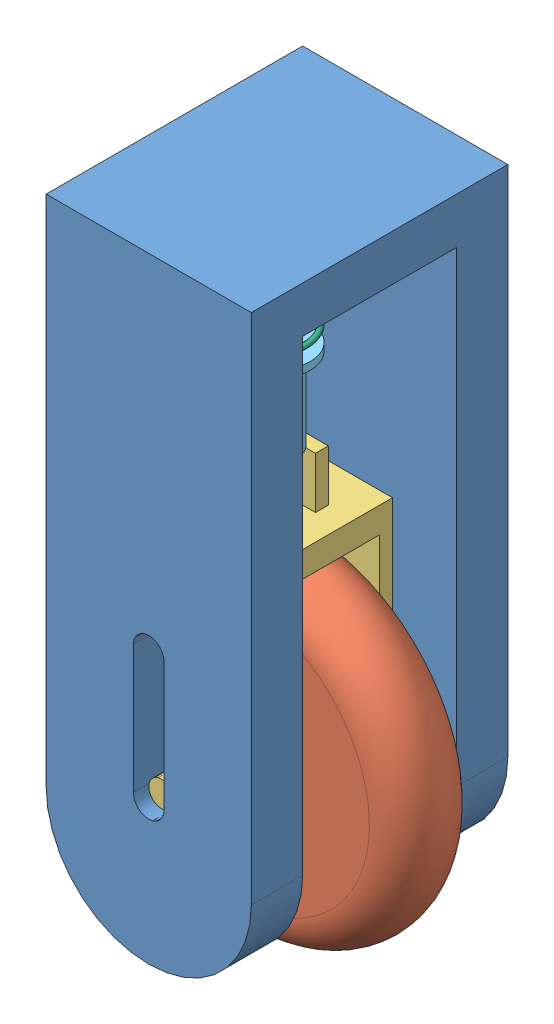
SolidWorks assembly Assem2, configuration Default. Lengths in mm.
Overall size (135.04 252.52 100).
6 component instances, 6 part files, 14 mates.
Components (placement in the parent):
- wheel-1: wheel [Default] at origin size (80 240 100)
- Part1^Assem2-1: Part1^Assem2 [Default] at (0 -125 0) x (0.999729 -0.023276 0) z (0 0 1) size (132 132 30) (virtual)
- Part2^Assem2-1: Part2^Assem2 [Default] at (0 -130 0) size (40 100 90) (virtual)
- Part3^Assem2-1: Part3^Assem2 [Default] at (0 -13 0) size (26 55 26) (virtual)
- Part4^Assem2-1: Part4^Assem2 [Default] at (0 -30 0) size (26 53 26) (virtual)
- Part7^Assem2-1: Part7^Assem2 [Default] at (0 5 0) x (1 0 0) z (0 1 0) size (30.02 26.11 26) (virtual)
Mates (geometry in assembly coordinates):
- Slot1: slot: cylinder of Part2^Assem2-1 through (0 -125 45) axis (0 0 -1) radius 5; plane of wheel-1 through (-6 -125 -50) normal (1 0 0); cylinder of wheel-1 through (0 -75 -50) axis (0 0 1) radius 6
- Width1: width: plane of assembly; plane of assembly; plane of assembly; plane of assembly; plane of Part2^Assem2-1 through (20 -60 -20) normal (0 0 1); plane of Part2^Assem2-1 through (20 -130 20) normal (0 0 -1); plane of wheel-1 through (0 -140 -50) normal (0 0 -1); plane of wheel-1 through (0 -140 50) normal (0 0 1)
- Concentric1: concentric: cylinder of assembly; cylinder of assembly; cylinder of Part1^Assem2-1 through (0 -125 0) axis (0 0 1) radius 6; cylinder of Part2^Assem2-1 through (0 -125 45) axis (0 0 -1) radius 5
- Width3: width: plane of assembly; plane of assembly; plane of assembly; plane of assembly; plane of Part1^Assem2-1 through (1.1871 -74.0138 15) normal (0 0 1); plane of Part1^Assem2-1 through (1.1871 -74.0138 -15) normal (0 0 -1); plane of Part2^Assem2-1 through (20 -130 25) normal (0 0 1); plane of Part2^Assem2-1 through (20 -50 -25) normal (0 0 -1)
- Concentric2: concentric: cylinder of assembly; cylinder of assembly; cylinder of wheel-1 through (0 37 -37.0711) axis (0 0 1) radius 2.5; cylinder of Part3^Assem2-1 through (0 37 -13) axis (0 0 1) radius 2.5
- Coincident1: coincident: plane of assembly through (0 0 0) normal (0 0 1); plane of Part3^Assem2-1 through (0 -13 0) normal (0 0 1); plane of assembly
- Parallel1: parallel: plane of assembly; plane of assembly; plane of wheel-1 through (-40 60 50) normal (0 1 0); plane of Part3^Assem2-1 through (0 32 -13) normal (0 1 0)
- Concentric4: concentric: cylinder of assembly; cylinder of assembly; cylinder of Part3^Assem2-1 through (0 -13 0) axis (0 -1 0) radius 5; cylinder of Part4^Assem2-1 through (0 -30 0) axis (0 -1 0) radius 8
- Concentric5: concentric: cylinder of assembly; cylinder of assembly; cylinder of Part2^Assem2-1 through (0 -40 -9.2426) axis (0 0 1) radius 1.5; cylinder of Part4^Assem2-1 through (0 -40 -13) axis (0 0 1) radius 2.5
- LimitDistance1: limit distance = 24 mm: plane of assembly; plane of assembly; plane of Part3^Assem2-1 through (0 29 -13) normal (0 -1 0); plane of Part4^Assem2-1 through (8 5 0) normal (0 1 0)
- InPlace3: in place: plane of Part4^Assem2-1 through (8 5 0) normal (0 1 0); plane of Part7^Assem2-1 through (0 5 0) normal (0 1 0); moOrthogonalPlaneRef_w of Part4^Assem2-1 through (8 5 0) normal (0 1 0); plane of Part7^Assem2-1 through (0 5 0) normal (0 0 -1); plane of Part4^Assem2-1 through (8 5 0) normal (0 1 0); plane of Part7^Assem2-1 through (0 5 0) normal (1 0 0); plane of Part4^Assem2-1 through (8 5 0) normal (0 1 0); unknown of Part7^Assem2-1
- Coincident8: coincident: plane of assembly through (8 5 0) normal (0 1 0); plane of assembly through (0 5 0) normal (0 1 0); plane of Part4^Assem2-1; plane of Part7^Assem2-1
- Coincident9: coincident: plane of assembly; plane of assembly; moOrthogonalPlaneRef_w of Part4^Assem2-1 through (0 5 0) normal (0 0 -1); plane of Part7^Assem2-1 through (0 5 0) normal (0 0 -1)
- Coincident10: coincident: plane of assembly; plane of assembly; moOrthogonalPlaneRef_w of Part4^Assem2-1 through (0 5 0) normal (-1 0 0); plane of Part7^Assem2-1 through (0 5 0) normal (1 0 0)
